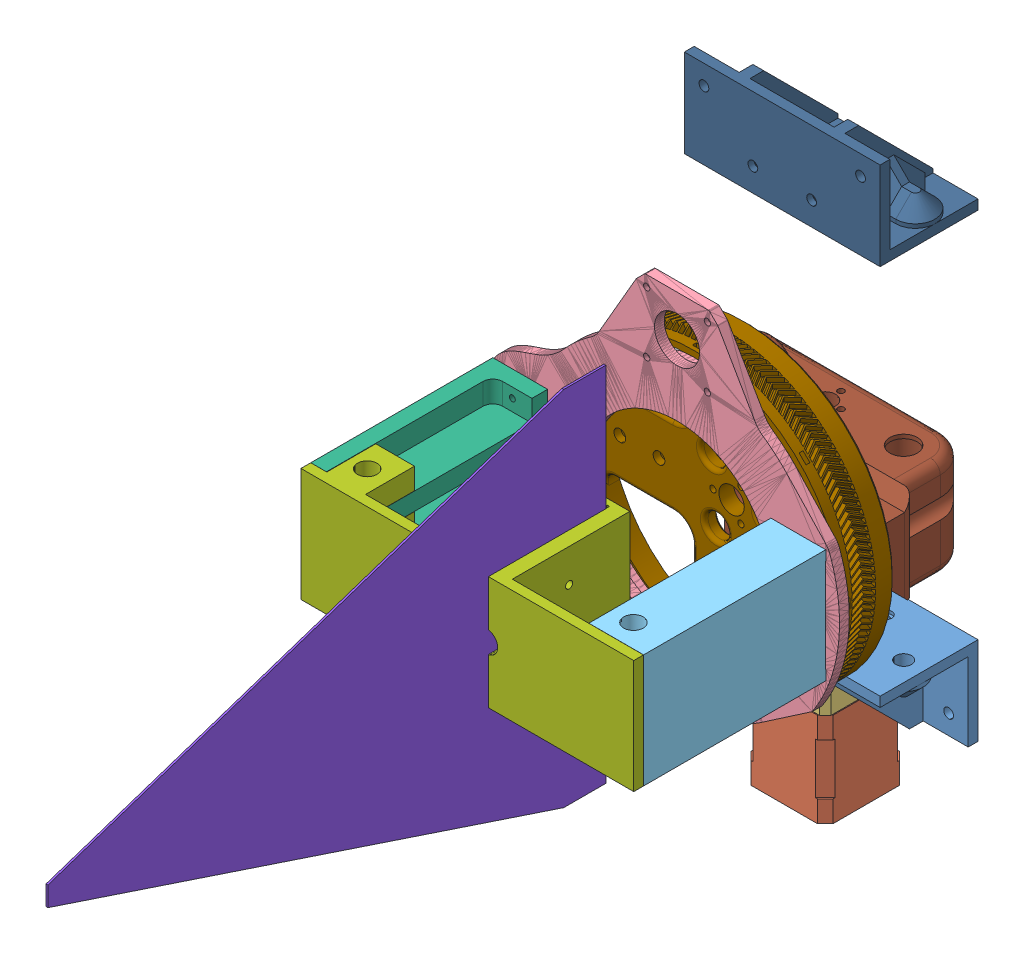
SolidWorks assembly wallmount_adjuster, configuration Default. Lengths in mm.
Overall size (181.35 308.37 429.23).
12 component instances, 11 part files, 0 mates.
Components (placement in the parent):
- bottom_wall_mount-1: bottom_wall_mount [Default] at origin size (100 45 50)
- Nema 17 Stepper Motor 17HD48002H-22B-1: Nema 17 Stepper Motor 17HD48002H-22B [Défaut] at (0.0105 -57.3724 3.0452) x (1 0 0) z (0 -1 0) size (42 54.3 72)
- Stepper_Spacer-1: Stepper_Spacer [Default] at (-0.0466 0.0261 2.9799) x (1 0 0) z (0 -1 0) size (42 42 20)
- Sunflower_logper_mount-1: Sunflower_logper_mount [Default] at (56.2116 -21.6584 217.222) x (-1 0 0) z (0 0 -1) size (181.35 197.43 341.88)
  - Pan_Mount_Sunflower_logper-1: Pan_Mount_Sunflower_logper [Default] at (59.0671 99.4425 141.3302) size (181.35 181.99 18.8)
  - Gear_Side_Support_sunflower_logper-1: Gear_Side_Support_sunflower_logper [Default] at (-16.9209 120.1353 133.2887) x (0 -1 0) z (1 0 0) size (58 98 28)
  - Idle_Side_Support_wallmount_sunflower_logper-1: Idle_Side_Support_wallmount_sunflower_logper [Default] at (153.0824 99.4817 133.241) x (0 1 0) z (-1 0 0) size (58 98 28)
  - logper_wallmount_holder-1: logper_wallmount_holder [Default] at (68.0819 99.4826 43.2299) size (170 58 65)
  - Logper_model-1: Logper_model [Default] at (58.3412 99.5165 -39.2495) x (0 0 -1) z (0 1 0) size (285 1 185)
- 144tooth_base_mount-1: 144tooth_base_mount [Default] at (0.0014 79.7804 53.3825) size (152.17 152.17 27)
- top_wall_mount-1: top_wall_mount [Default] at (0 200 0) x (1 0 0) z (0 0 -1) size (100 45 50)
- carriage-1: carriage [Default] at (0 100 3) x (0 0 -1) z (0 -1 0) size (55.95 128 128)
